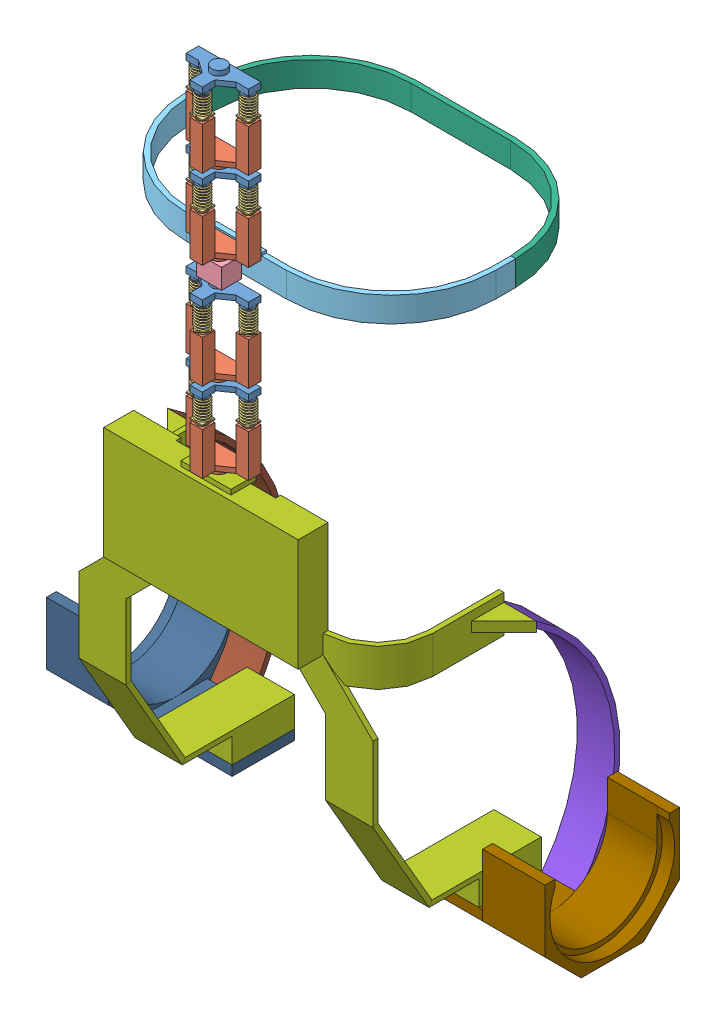
SolidWorks assembly torso_v3, configuration Default. Lengths in mm.
Overall size (400 579.94 220.1).
28 component instances, 11 part files, 75 mates.
Components (placement in the parent):
- unit_p1-1: unit_p1 [Default] at (27.4082 24.1929 24.0012) size (50 11 27)
- unit_p2-1: unit_p2 [Default] at (27.4082 -27.8071 24.0012) x (-1 0 0) z (0 0 1) size (50 38 27)
- unit_pole_b-1: unit_pole_b [Default] at (7.4082 4.1929 24.0012) size (12.02 47.5 12.62)
- unit_pole_b-2: unit_pole_b [Default] at (27.4082 4.1929 41.0012) x (0 0 -1) z (1 0 0) size (12.02 47.5 12.62)
- unit_pole_b-3: unit_pole_b [Default] at (47.4082 4.1929 24.0012) size (12.02 47.5 12.62)
- unit_p1-2: unit_p1 [Default] at (27.4082 -39.8071 24.0012) size (50 11 27)
- unit_p2-2: unit_p2 [Default] at (27.4082 -91.8071 24.0012) x (-1 0 0) z (0 0 1) size (50 38 27)
- unit_pole_b-4: unit_pole_b [Default] at (7.4082 -59.8071 24.0012) x (0.99966 0 -0.026086) z (0.026086 0 0.99966) size (12.02 47.5 12.62)
- unit_pole_b-5: unit_pole_b [Default] at (27.4082 -59.8071 41.0012) size (12.02 47.5 12.62)
- unit_pole_b-6: unit_pole_b [Default] at (47.4082 -59.8071 24.0012) size (12.02 47.5 12.62)
- waist_rotate_v3-1: waist_rotate_v3 [默认] at (27.4082 -107.8071 27.6012) x (-1 0 0) z (0 0 1) size (20 24 18)
- waist_back-1: waist_back [Default] at (27.4082 -96.8071 21.6012) x (1 0 0) z (0 0 -1) size (248 22 104)
- front_a-1: front_a [Default] at (27.4082 -97.8071 -86.3988) x (1 0 0) z (0 0 -1) size (248 20 84)
- unit_p1-3: unit_p1 [Default] at (27.4082 -123.8071 24.0012) size (50 11 27)
- unit_p2-3: unit_p2 [Default] at (27.4082 -175.8071 24.0012) x (-1 0 0) z (0 0 1) size (50 38 27)
- unit_pole_b-7: unit_pole_b [Default] at (7.4082 -143.8071 24.0012) x (0.627764 0 -0.778403) z (0.778403 0 0.627764) size (12.02 47.5 12.62)
- unit_pole_b-8: unit_pole_b [Default] at (47.4082 -143.8071 24.0012) x (-0.721684 0 0.692222) z (-0.692222 0 -0.721684) size (12.02 47.5 12.62)
- unit_pole_b-9: unit_pole_b [Default] at (27.4082 -143.8071 41.0012) x (-0.692241 0 0.721666) z (-0.721666 0 -0.692241) size (12.02 47.5 12.62)
- unit_p1-4: unit_p1 [Default] at (27.4082 -187.8071 24.0012) size (50 11 27)
- unit_p2-4: unit_p2 [Default] at (27.4082 -239.8071 24.0012) x (-1 0 0) z (0 0 1) size (50 38 27)
- unit_pole_b-10: unit_pole_b [Default] at (7.4082 -207.8071 24.0012) x (0.998417 0 -0.056251) z (0.056251 0 0.998417) size (12.02 47.5 12.62)
- unit_pole_b-11: unit_pole_b [Default] at (27.4082 -207.8071 41.0012) x (0.99954 0 0.030344) z (-0.030344 0 0.99954) size (12.02 47.5 12.62)
- unit_pole_b-12: unit_pole_b [Default] at (47.4082 -207.8071 24.0012) x (-0.067406 0 0.997726) z (-0.997726 0 -0.067406) size (12.02 47.5 12.62)
- torso_back-1: torso_back [Default] at (27.4082 -291.8071 18.1012) x (-1 0 0) z (0 0 1) size (296 295.94 155)
- addtion_v0.1-1: addtion_v0.1 [Default] at (175.4082 -486.3955 -78.8988) x (-1 0 0) z (0 0 1) size (30 213.78 67.22)
- torso_shoulder-1: torso_shoulder [默认] at (107.4082 -543.7494 -87.8988) x (0 0 1) z (1 0 0) size (108 79.05 120)
- torso_shoulder_v0.3-1: torso_shoulder_v0.3 [默认] at (-52.5918 -543.7494 -87.8988) x (0 0 -1) z (-1 0 0) size (108 79.05 120)
- addtion_v0.3-1: addtion_v0.3 [Default] at (-90.5918 -486.3955 -78.8988) x (-1 0 0) z (0 0 1) size (30 213.78 67.22)
Mates (geometry in assembly coordinates):
- 同心1: concentric aligned: cylinder of unit_p2-1 through (7.4082 -27.8071 24.0012) axis (0 1 0) radius 4; cylinder of unit_pole_b-1 through (7.4082 -25.8071 24.0012) axis (0 1 0) radius 4
- 同心2: concentric aligned: cylinder of unit_p1-1 through (7.4082 21.1929 24.0012) axis (0 1 0) radius 5; cylinder of unit_pole_b-1 through (7.4082 -25.8071 24.0012) axis (0 1 0) radius 4
- 重合1: coincident anti-aligned: plane of unit_p1-1 through (7.4082 21.1929 24.0012) normal (0 -1 0); plane of unit_pole_b-1 through (7.4082 21.1929 24.0012) normal (0 1 0)
- 同心3: concentric aligned: cylinder of unit_p2-1 through (47.4082 -27.8071 24.0012) axis (0 1 0) radius 4; cylinder of unit_pole_b-3 through (47.4082 -25.8071 24.0012) axis (0 1 0) radius 4
- 重合2: coincident anti-aligned: plane of unit_p1-1 through (47.4082 21.1929 24.0012) normal (0 -1 0); plane of unit_pole_b-3 through (47.4082 21.1929 24.0012) normal (0 1 0)
- 同心4: concentric aligned: cylinder of unit_p2-1 through (27.4082 -27.8071 41.0012) axis (0 1 0) radius 4; cylinder of unit_pole_b-2 through (27.4082 -25.8071 41.0012) axis (0 1 0) radius 4
- 重合3: coincident anti-aligned: plane of unit_p1-1 through (27.4082 21.1929 41.0012) normal (0 -1 0); plane of unit_pole_b-2 through (27.4082 21.1929 41.0012) normal (0 1 0)
- 同心5: concentric aligned: cylinder of unit_p1-1 through (27.4082 21.1929 41.0012) axis (0 1 0) radius 5; cylinder of unit_pole_b-2 through (27.4082 -25.8071 41.0012) axis (0 1 0) radius 4
- 同心6: concentric aligned: cylinder of unit_p1-1 through (47.4082 21.1929 24.0012) axis (0 1 0) radius 5; cylinder of unit_pole_b-3 through (47.4082 -25.8071 24.0012) axis (0 1 0) radius 4
- 同心7: concentric anti-aligned: cylinder of unit_p2-1 through (27.4082 -35.8071 27.6012) axis (0 1 0) radius 7; cylinder of unit_p1-2 through (27.4082 -31.8071 27.6012) axis (0 -1 0) radius 6
- 重合4: coincident anti-aligned: plane of unit_p2-1 through (27.4082 -31.8071 24.0012) normal (0 -1 0); plane of unit_p1-2 through (27.4082 -31.8071 27.6012) normal (0 1 0)
- 同心8: concentric aligned: cylinder of unit_p2-2 through (47.4082 -91.8071 24.0012) axis (0 1 0) radius 4; cylinder of unit_pole_b-6 through (47.4082 -89.8071 24.0012) axis (0 1 0) radius 4
- 同心9: concentric aligned: cylinder of unit_p2-2 through (27.4082 -91.8071 41.0012) axis (0 1 0) radius 4; cylinder of unit_pole_b-5 through (27.4082 -89.8071 41.0012) axis (0 1 0) radius 4
- 同心10: concentric aligned: cylinder of unit_p2-2 through (7.4082 -91.8071 24.0012) axis (0 1 0) radius 4; cylinder of unit_pole_b-4 through (7.4082 -89.8071 24.0012) axis (0 1 0) radius 4
- 同心11: concentric aligned: cylinder of unit_p1-2 through (7.4082 -42.8071 24.0012) axis (0 1 0) radius 5; cylinder of unit_pole_b-4 through (7.4082 -89.8071 24.0012) axis (0 1 0) radius 4
- 同心12: concentric aligned: cylinder of unit_p1-2 through (27.4082 -42.8071 41.0012) axis (0 1 0) radius 5; cylinder of unit_pole_b-5 through (27.4082 -89.8071 41.0012) axis (0 1 0) radius 4
- 同心13: concentric aligned: cylinder of unit_p1-2 through (47.4082 -42.8071 24.0012) axis (0 1 0) radius 5; cylinder of unit_pole_b-6 through (47.4082 -89.8071 24.0012) axis (0 1 0) radius 4
- 距离1: distance = 52 mm anti-aligned: plane of unit_p2-1 through (27.4082 -27.8071 24.0012) normal (0 1 0); plane of unit_p1-1 through (27.4082 24.1929 24.0012) normal (0 -1 0)
- 平行1: parallel aligned: plane of unit_p2-1 through (32.4082 2.1929 36.0012) normal (0 0 -1); plane of unit_pole_b-2 through (32.4082 5.1929 36.0012) normal (0 0 -1)
- 重合5: coincident aligned: plane of unit_p2-1 through (2.4082 -31.8071 19.0012) normal (0 0 -1); plane of unit_pole_b-3 through (42.4082 5.1929 19.0012) normal (0 0 -1)
- 重合6: coincident aligned: plane of unit_p2-1 through (2.4082 -31.8071 19.0012) normal (0 0 -1); plane of unit_pole_b-1 through (2.4082 5.1929 19.0012) normal (0 0 -1)
- 重合7: coincident anti-aligned: plane of unit_p1-2 through (7.4082 -42.8071 24.0012) normal (0 -1 0); plane of unit_pole_b-4 through (7.4082 -42.8071 24.0012) normal (0 1 0)
- 重合8: coincident anti-aligned: plane of unit_p1-2 through (27.4082 -42.8071 41.0012) normal (0 -1 0); plane of unit_pole_b-5 through (27.4082 -42.8071 41.0012) normal (0 1 0)
- 重合9: coincident anti-aligned: plane of unit_p1-2 through (47.4082 -42.8071 24.0012) normal (0 -1 0); plane of unit_pole_b-6 through (47.4082 -42.8071 24.0012) normal (0 1 0)
- 距离2: distance = 52 mm anti-aligned: plane of unit_p1-2 through (27.4082 -39.8071 24.0012) normal (0 -1 0); plane of unit_p2-2 through (27.4082 -91.8071 24.0012) normal (0 1 0)
- 重合11: coincident anti-aligned: plane of waist_rotate_v3-1 through (27.4082 -107.8071 17.6012) normal (0 0 -1); plane of waist_back-1 through (26.1216 -107.8071 29.982) normal (0 0 1)
- 同心15: concentric anti-aligned: cylinder of waist_rotate_v3-1 through (27.4082 -107.8071 17.6012) axis (0 0 1) radius 6; cylinder of waist_back-1 through (26.1216 -107.8071 29.982) axis (0 0 -1) radius 6
- 重合12: coincident anti-aligned: plane of waist_back-1 through (-98.0505 -115.3762 -74.018) normal (0 0 -1); plane of front_a-1 through (-96.7639 -115.3762 -86.3988) normal (0 0 1)
- 重合13: coincident aligned: plane of waist_back-1 through (-13.6748 -97.0255 -58.018) normal (0.019589 0.999808 0); plane of front_a-1 through (67.5964 -98.5926 -86.3988) normal (0.019589 0.999808 0)
- 重合14: coincident aligned: line of waist_back-1 through (-98.0505 -115.3762 -74.018) axis (0.019589 0.999808 0); line of front_a-1 through (-96.7639 -115.3762 -86.3988) axis (0.019589 0.999808 0)
- 同心18: concentric aligned: cylinder of unit_p2-3 through (7.4082 -175.8071 24.0012) axis (0 1 0) radius 4; cylinder of unit_pole_b-7 through (7.4082 -173.8071 24.0012) axis (0 1 0) radius 4
- 同心19: concentric aligned: cylinder of unit_p2-3 through (27.4082 -175.8071 41.0012) axis (0 1 0) radius 4; cylinder of unit_pole_b-9 through (27.4082 -173.8071 41.0012) axis (0 1 0) radius 4
- 同心20: concentric aligned: cylinder of unit_p2-3 through (47.4082 -175.8071 24.0012) axis (0 1 0) radius 4; cylinder of unit_pole_b-8 through (47.4082 -173.8071 24.0012) axis (0 1 0) radius 4
- 重合17: coincident anti-aligned: plane of unit_p1-3 through (47.4082 -126.8071 24.0012) normal (0 -1 0); plane of unit_pole_b-8 through (47.4082 -126.8071 24.0012) normal (0 1 0)
- 重合18: coincident anti-aligned: plane of unit_p1-3 through (47.4082 -126.8071 24.0012) normal (0 -1 0); plane of unit_pole_b-9 through (27.4082 -126.8071 41.0012) normal (0 1 0)
- 同心23: concentric aligned: cylinder of unit_p1-3 through (7.4082 -126.8071 24.0012) axis (0 1 0) radius 5; cylinder of unit_pole_b-7 through (7.4082 -173.8071 24.0012) axis (0 1 0) radius 4
- 同心24: concentric aligned: cylinder of unit_p1-3 through (27.4082 -126.8071 41.0012) axis (0 1 0) radius 5; cylinder of unit_pole_b-9 through (27.4082 -173.8071 41.0012) axis (0 1 0) radius 4
- 重合19: coincident anti-aligned: plane of unit_p1-3 through (7.4082 -126.8071 24.0012) normal (0 -1 0); plane of unit_pole_b-7 through (7.4082 -126.8071 24.0012) normal (0 1 0)
- 距离3: distance = 52 mm anti-aligned: plane of unit_p1-3 through (27.4082 -123.8071 24.0012) normal (0 -1 0); plane of unit_p2-3 through (27.4082 -175.8071 24.0012) normal (0 1 0)
- 同心26: concentric anti-aligned: cylinder of unit_p2-2 through (27.4082 -99.8071 27.6012) axis (0 1 0) radius 7; cylinder of waist_rotate_v3-1 through (27.4082 -95.8071 27.6012) axis (0 -1 0) radius 4
- 重合21: coincident anti-aligned: plane of unit_p2-2 through (27.4082 -95.8071 24.0012) normal (0 -1 0); plane of waist_rotate_v3-1 through (27.4082 -95.8071 27.6012) normal (0 1 0)
- 同心27: concentric anti-aligned: cylinder of waist_rotate_v3-1 through (27.4082 -119.8071 27.6012) axis (0 1 0) radius 3; cylinder of unit_p1-3 through (27.4082 -115.8071 27.6012) axis (0 -1 0) radius 6
- 重合22: coincident anti-aligned: plane of waist_rotate_v3-1 through (27.4082 -119.8071 27.6012) normal (0 -1 0); plane of unit_p1-3 through (27.4082 -119.8071 24.0012) normal (0 1 0)
- 平行2: parallel aligned: plane of unit_p2-2 through (2.4082 -95.8071 19.0012) normal (0 0 -1); plane of unit_p1-3 through (52.4082 -119.8071 19.0012) normal (0 0 -1)
- 同心28: concentric anti-aligned: cylinder of unit_p2-3 through (27.4082 -183.8071 27.6012) axis (0 1 0) radius 7; cylinder of unit_p1-4 through (27.4082 -179.8071 27.6012) axis (0 -1 0) radius 6
- 重合23: coincident anti-aligned: plane of unit_p2-3 through (27.4082 -179.8071 24.0012) normal (0 -1 0); plane of unit_p1-4 through (27.4082 -179.8071 27.6012) normal (0 1 0)
- 同心29: concentric aligned: cylinder of unit_p2-4 through (7.4082 -239.8071 24.0012) axis (0 1 0) radius 4; cylinder of unit_pole_b-10 through (7.4082 -237.8071 24.0012) axis (0 1 0) radius 4
- 同心30: concentric aligned: cylinder of unit_p2-4 through (27.4082 -239.8071 41.0012) axis (0 1 0) radius 4; cylinder of unit_pole_b-11 through (27.4082 -237.8071 41.0012) axis (0 1 0) radius 4
- 同心31: concentric aligned: cylinder of unit_p2-4 through (47.4082 -239.8071 24.0012) axis (0 1 0) radius 4; cylinder of unit_pole_b-12 through (47.4082 -237.8071 24.0012) axis (0 1 0) radius 4
- 同心32: concentric aligned: cylinder of unit_p1-4 through (47.4082 -190.8071 24.0012) axis (0 1 0) radius 5; cylinder of unit_pole_b-12 through (47.4082 -237.8071 24.0012) axis (0 1 0) radius 4
- 同心33: concentric aligned: cylinder of unit_p1-4 through (27.4082 -190.8071 41.0012) axis (0 1 0) radius 5; cylinder of unit_pole_b-11 through (27.4082 -237.8071 41.0012) axis (0 1 0) radius 4
- 同心34: concentric aligned: cylinder of unit_p1-4 through (7.4082 -190.8071 24.0012) axis (0 1 0) radius 5; cylinder of unit_pole_b-10 through (7.4082 -237.8071 24.0012) axis (0 1 0) radius 4
- 重合24: coincident anti-aligned: plane of unit_p1-4 through (7.4082 -190.8071 24.0012) normal (0 -1 0); plane of unit_pole_b-10 through (7.4082 -190.8071 24.0012) normal (0 1 0)
- 重合25: coincident anti-aligned: plane of unit_p1-4 through (27.4082 -190.8071 41.0012) normal (0 -1 0); plane of unit_pole_b-11 through (27.4082 -190.8071 41.0012) normal (0 1 0)
- 重合26: coincident anti-aligned: plane of unit_p1-4 through (47.4082 -190.8071 24.0012) normal (0 -1 0); plane of unit_pole_b-12 through (47.4082 -190.8071 24.0012) normal (0 1 0)
- 距离4: distance = 52 mm anti-aligned: plane of unit_p1-4 through (27.4082 -187.8071 24.0012) normal (0 -1 0); plane of unit_p2-4 through (27.4082 -239.8071 24.0012) normal (0 1 0)
- 平行3: parallel aligned: plane of unit_p2-3 through (2.4082 -179.8071 19.0012) normal (0 0 -1); plane of unit_p2-4 through (2.4082 -243.8071 19.0012) normal (0 0 -1)
- 同心35: concentric anti-aligned: cylinder of unit_p2-4 through (27.4082 -247.8071 27.6012) axis (0 1 0) radius 7; cylinder of torso_back-1 through (27.4082 -243.8071 27.6012) axis (0 -1 0) radius 6
- 重合27: coincident anti-aligned: plane of unit_p2-4 through (27.4082 -243.8071 24.0012) normal (0 -1 0); plane of torso_back-1 through (27.4082 -243.8071 27.6012) normal (0 1 0)
- 平行4: parallel aligned: plane of unit_p2-4 through (2.4082 -243.8071 19.0012) normal (0 0 -1); plane of torso_back-1 through (27.4082 -291.8071 18.1012) normal (0 0 -1)
- 重合28: coincident anti-aligned: plane of torso_back-1 through (27.4082 -539.7494 18.1012) normal (0 -1 0); plane of torso_shoulder-1 through (107.4082 -539.7494 -112.8988) normal (0 1 0)
- 重合29: coincident aligned: plane of torso_back-1 through (107.4082 -515.7494 -22.8988) normal (-1 0 0); plane of torso_shoulder-1 through (107.4082 -543.7494 -87.8988) normal (-1 0 0)
- 重合30: coincident aligned: plane of torso_back-1 through (145.4082 -539.7494 -62.8988) normal (0 0 1); plane of torso_shoulder-1 through (107.4082 -547.7494 -62.8988) normal (0 0 1)
- 平行5: parallel aligned: plane of unit_p2-1 through (2.4082 -31.8071 19.0012) normal (0 0 -1); plane of unit_p2-2 through (2.4082 -95.8071 19.0012) normal (0 0 -1)
- 重合34: coincident anti-aligned: plane of torso_back-1 through (149.4082 -356.8071 -78.8988) normal (0 0 -1); plane of addtion_v0.1-1 through (145.4082 -338.8298 -78.8988) normal (0 0 1)
- 重合35: coincident: line of torso_back-1 through (175.4082 -333.8071 -78.8988) axis (0 -1 0); plane of addtion_v0.1-1 through (175.4082 -455.6056 -2.1719) normal (1 0 0)
- 重合36: coincident aligned: line of torso_back-1 through (149.4082 -333.8071 -78.8988) axis (1 0 0); line of addtion_v0.1-1 through (145.4082 -333.8071 -78.8988) axis (1 0 0)
- 重合37: coincident anti-aligned: plane of torso_back-1 through (27.4082 -539.7494 18.1012) normal (0 -1 0); plane of torso_shoulder_v0.3-1 through (-52.5918 -539.7494 -62.8988) normal (0 1 0)
- 重合38: coincident aligned: plane of torso_back-1 through (27.4082 -515.7494 -112.8988) normal (0 0 -1); plane of torso_shoulder_v0.3-1 through (-52.5918 -547.7494 -112.8988) normal (0 0 -1)
- 重合39: coincident aligned: plane of torso_back-1 through (-52.5918 -515.7494 -22.8988) normal (1 0 0); plane of torso_shoulder_v0.3-1 through (-52.5918 -543.7494 -87.8988) normal (1 0 0)
- 重合40: coincident anti-aligned: plane of torso_back-1 through (-94.5918 -356.8071 -78.8988) normal (0 0 -1); plane of addtion_v0.3-1 through (-120.5918 -338.8298 -78.8988) normal (0 0 1)
- 重合41: coincident anti-aligned: line of torso_back-1 through (-120.5918 -333.8071 -78.8988) axis (0 -1 0); line of addtion_v0.3-1 through (-120.5918 -338.8298 -78.8988) axis (0 1 0)
- 重合42: coincident aligned: line of torso_back-1 through (-120.5918 -333.8071 -78.8988) axis (1 0 0); line of addtion_v0.3-1 through (-120.5918 -333.8071 -78.8988) axis (1 0 0)
- 平行6: parallel aligned: plane of unit_p2-2 through (32.4082 -95.8071 46.0012) normal (0 0 1); plane of waist_rotate_v3-1 through (37.4082 -115.8071 35.6012) normal (0 0 1)
- 平行7: parallel aligned: plane of unit_p2-2 through (27.4082 -95.8071 24.0012) normal (0 -1 0); plane of waist_back-1
